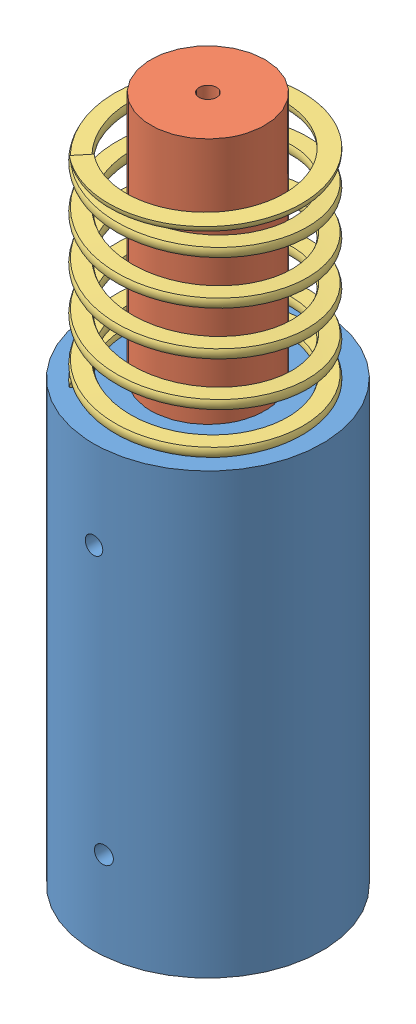
SolidWorks assembly suspension, configuration Default. Lengths in mm.
Overall size (32.71 78.15 32.71).
3 component instances, 3 part files, 3 mates.
Components (placement in the parent):
- suspension 1-1: suspension 1 [Default] at (-14.0996 -35.3728 6.6744) size (26 50 26)
- suspension 2-1: suspension 2 [Default] at (-14.0996 -27.2249 6.6744) x (0.4026 0 -0.915376) z (0.915376 0 0.4026) size (13 70 13)
- spring-1: spring [Default] at (-14.0665 37.5022 7.0045) x (0.773571 0 0.63371) z (0 -1 0) size (23.25 23.23 23.91)
Mates (geometry in assembly coordinates):
- Coincident1: coincident anti-aligned: plane of suspension 1-1 through (-14.0996 14.6272 6.6744) normal (0 1 0); plane of spring-1 through (17.292 14.6272 46.9132) normal (0 -1 0)
- Parallel1: parallel aligned: plane of suspension 2-1 through (-14.0996 42.7751 6.6744) normal (0 1 0); plane of spring-1 through (18.2163 37.5022 47.6703) normal (0 1 0)
- Concentric1: concentric aligned: circle of suspension 1-1; circle of suspension 2-1
